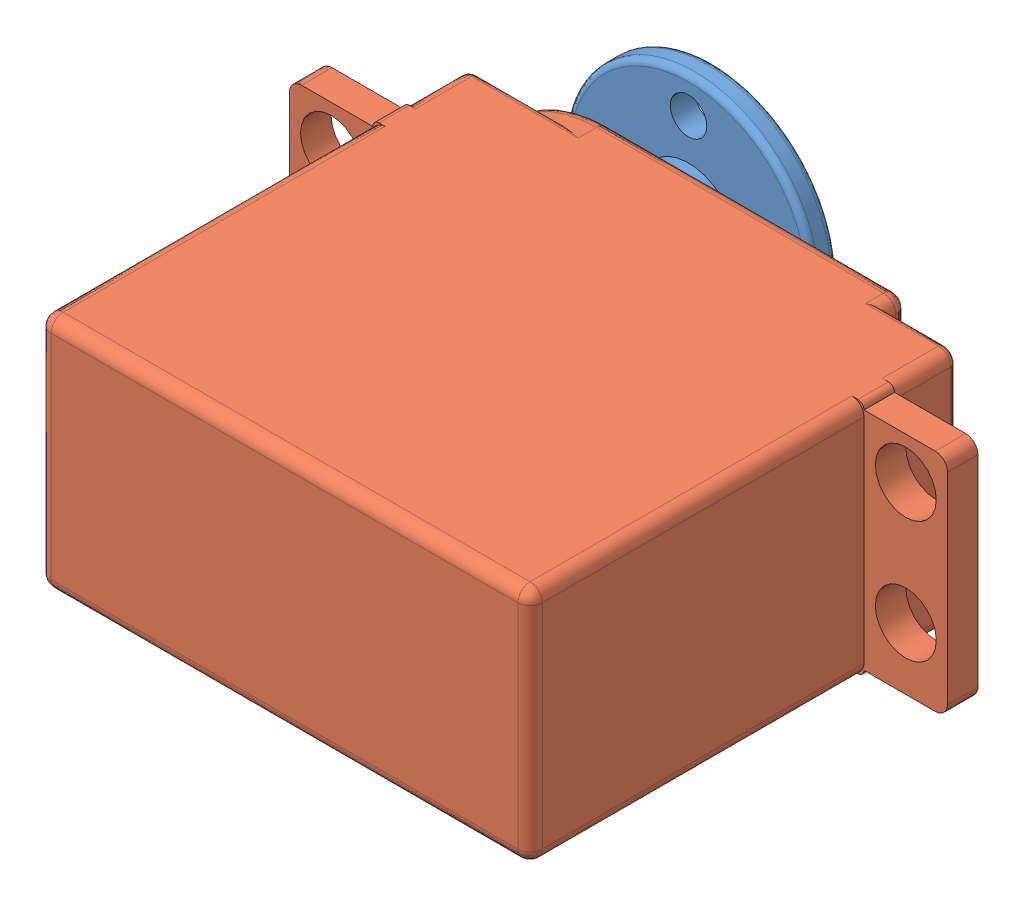
SolidWorks assembly 六足机器人装配图, configuration 默认. Lengths in mm.
Overall size (54 20.5 45).
2 component instances, 2 part files, 2 mates.
Components (placement in the parent):
- 舵盘-1: 舵盘 [默认] at (-12.3633 0.1072 0) size (20.5 20.5 5)
- MG995舵机-2: MG995舵机 [默认] at (-14.0275 9.1438 10) size (54 19.5 43)
Mates (geometry in assembly coordinates):
- 重合6: coincident: plane of 舵盘-1 through (-12.3633 0.1072 2) normal (0 0 1); plane of MG995舵机-2 through (-3.1184 -26.4564 2) normal (0 0 -1)
- 同心1: concentric anti-aligned: circle of 舵盘-1; circle of MG995舵机-2
